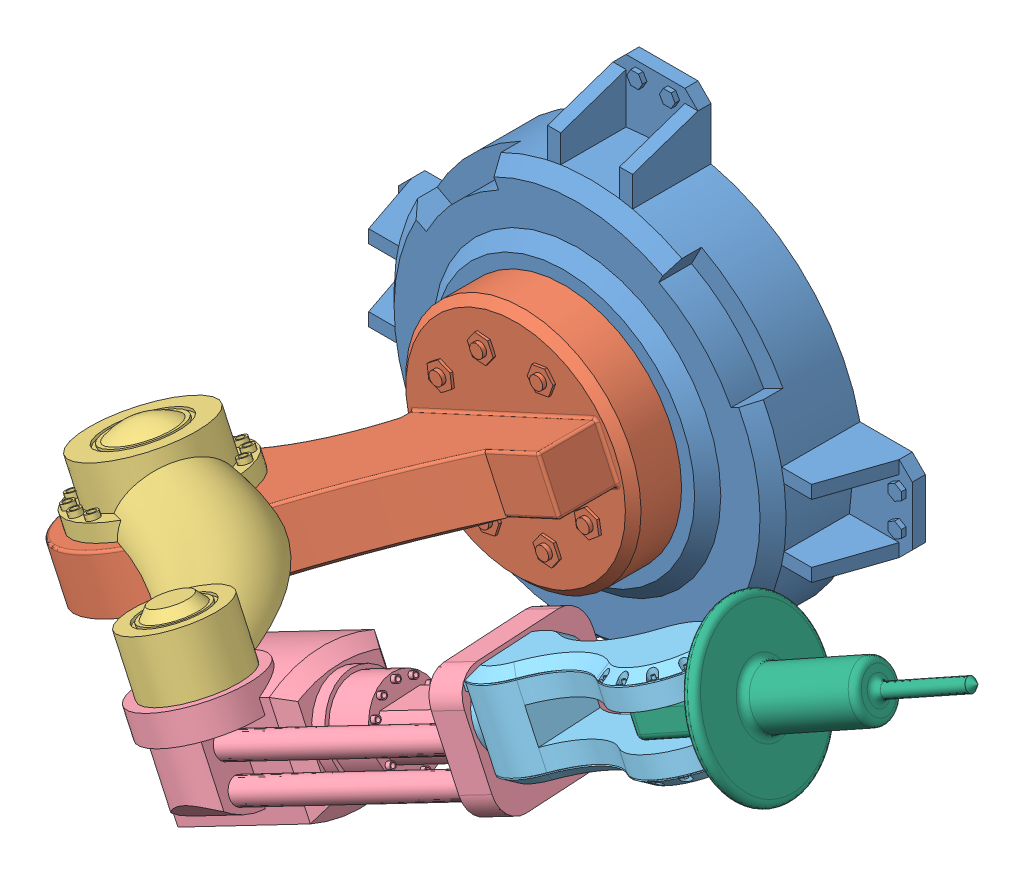
SolidWorks assembly Assem1, configuration Default. Lengths in mm.
Overall size (1115.95 601.3 581.7).
6 component instances, 6 part files, 11 mates.
Components (placement in the parent):
- Part1-1: Part1 [Default] at (-120.3537 284.3729 348.5488) size (392.87 392.87 100)
- Part2-1: Part2 [Default] at (-116.8731 285.9817 584.773) x (-0.907722 -0.419572 0) z (0 0 1) size (308.5 180 228.5)
- Part3-1: Part3 [Default] at (-256.512 221.4371 588.5488) x (0.702172 0.324561 0.633731) z (0.419572 -0.907722 0) size (759.16 130.05 131.95)
- Part4-1: Part4 [Default] at (-10.7518 335.0336 810.3545) x (0.902134 0.416989 -0.11079) z (0.419572 -0.907722 0) size (275 132.5 105.88)
- Part5-1: Part5 [Default] at (311.5999 484.0327 770.7669) x (0.902134 0.416989 -0.11079) z (0.419572 -0.907722 0) size (193 80 70)
- Part6-1: Part6 [Default] at (311.5999 484.0327 770.7669) x (0.891241 0.411954 -0.189695) z (0.419572 -0.907722 0) size (230 120 120)
Mates (geometry in assembly coordinates):
- Coincident1: coincident anti-aligned: plane of Part1-1 through (-120.3537 284.3729 428.5488) normal (0 0 1); plane of Part2-1 through (-120.3537 284.3729 428.5488) normal (0 0 -1)
- Concentric9: concentric aligned: cylinder of Part1-1 through (-120.3537 284.3729 448.5488) axis (0 0 -1) radius 15; cylinder of Part2-1 through (-120.3537 284.3729 448.5488) axis (0 0 -1) radius 15
- Coincident2: coincident anti-aligned: plane of Part2-1 through (-199.0936 270.0105 510.5488) normal (-0.419572 0.907722 0); plane of Part3-1 through (-264.9034 239.5916 588.5488) normal (0.419572 -0.907722 0)
- Concentric10: concentric aligned: cylinder of Part2-1 through (-256.512 221.4371 588.5488) axis (-0.419572 0.907722 0) radius 15; cylinder of Part3-1 through (-256.512 221.4371 588.5488) axis (-0.419572 0.907722 0) radius 15
- Coincident4: coincident anti-aligned: plane of Part3-1 through (-264.9034 239.5916 588.5488) normal (0.419572 -0.907722 0); plane of Part4-1 through (-19.1433 353.1881 810.3545) normal (-0.419572 0.907722 0)
- Coincident8: coincident anti-aligned: plane of Part4-1 through (209.1777 394.8276 795.3652) normal (0.902134 0.416989 -0.11079); plane of Part5-1 through (192.2283 428.8562 785.4267) normal (-0.902134 -0.416989 0.11079)
- Concentric14: concentric anti-aligned: cylinder of Part4-1 through (192.2283 428.8562 785.4267) axis (-0.902134 -0.416989 0.11079) radius 15; cylinder of Part5-1 through (174.1856 420.5164 787.6425) axis (0.902134 0.416989 -0.11079) radius 15
- Parallel2: parallel aligned: plane of Part4-1 through (190.2105 441.1434 815.2421) normal (0.100567 0.046484 0.993844); plane of Part5-1 through (186.1621 456.3478 812.4251) normal (0.100567 0.046484 0.993844)
- Concentric15: concentric aligned: cylinder of Part3-1 through (-10.7518 335.0336 810.3545) axis (-0.419572 0.907722 0) radius 15; cylinder of Part4-1 through (-10.7518 335.0336 810.3545) axis (-0.419572 0.907722 0) radius 15
- Coincident10: coincident anti-aligned: plane of Part5-1 through (186.9837 440.2027 785.4267) normal (0.419572 -0.907722 0); plane of Part6-1 through (292.4047 488.9309 796.6522) normal (-0.419572 0.907722 0)
- Concentric16: concentric aligned: cylinder of Part5-1 through (302.1595 504.4564 770.7669) axis (0.419572 -0.907722 0) radius 10; cylinder of Part6-1 through (302.1595 504.4564 770.7669) axis (0.419572 -0.907722 0) radius 10
